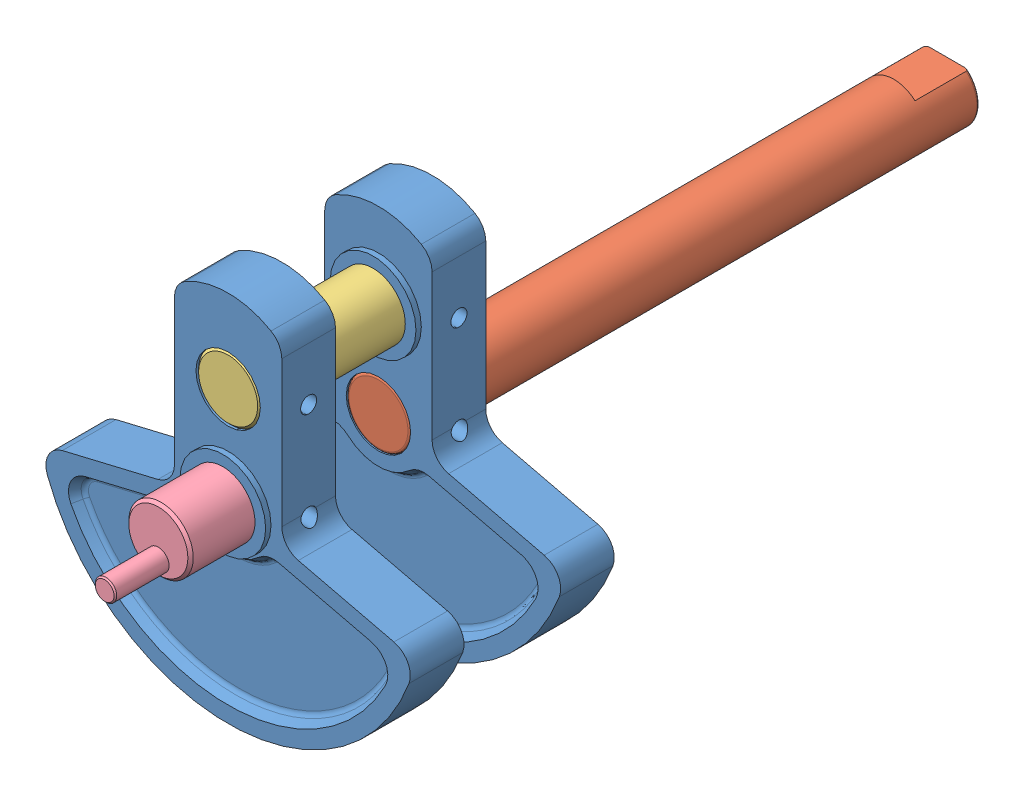
SolidWorks assembly Assembly Crankshaft, configuration Default. Lengths in mm.
Overall size (33.96 34.76 78.53).
5 component instances, 4 part files, 8 mates.
Components (placement in the parent):
- Crankshaft Counterweight-1: Crankshaft Counterweight [Default] at (4.4861 16.4045 32.7559) size (33.96 34.76 6)
- Crankshaft-3: Crankshaft [Default] at (4.4861 16.4045 35.2559) x (-1 0 0) z (0 0 -1) size (6 6 53.03)
- Crankshaft pin-1: Crankshaft pin [Default] at (4.4861 25.4045 30.2559) size (6 6 19)
- Crankshaft Counterweight-2: Crankshaft Counterweight [Default] at (4.4861 16.4045 46.7559) x (-1 0 0) z (0 0 -1) size (33.96 34.76 6)
- Crankshaft valve crank-1: Crankshaft valve crank [Default] at (4.4861 16.4045 44.2559) x (1 0 0) z (0 -1 0) size (6 16.5 6)
Mates (geometry in assembly coordinates):
- Coincident1: coincident aligned: line of Crankshaft Counterweight-1 through (9.4861 16.4045 32.7559) axis (-1 0 0); line of Crankshaft-3 through (7.4861 16.4045 32.7559) axis (-1 0 0)
- Concentric1: concentric aligned: cylinder of Crankshaft Counterweight-1 through (4.4861 16.4045 30.2559) axis (0 0 1) radius 3; cylinder of Crankshaft-3 through (4.4861 16.4045 -17.7441) axis (0 0 1) radius 3
- Coincident2: coincident anti-aligned: line of Crankshaft Counterweight-1 through (9.4861 25.4045 32.7559) axis (-1 0 0); line of Crankshaft pin-1 through (1.4861 25.4045 32.7559) axis (1 0 0)
- Concentric2: concentric anti-aligned: cylinder of Crankshaft Counterweight-1 through (4.4861 25.4045 29.7559) axis (0 0 1) radius 3; cylinder of Crankshaft pin-1 through (4.4861 25.4045 49.2559) axis (0 0 -1) radius 3
- Coincident3: coincident aligned: line of Crankshaft pin-1 through (1.4861 25.4045 46.7559) axis (1 0 0); line of Crankshaft Counterweight-2 through (7.4861 25.4045 46.7559) axis (1 0 0)
- Concentric3: concentric aligned: cylinder of Crankshaft pin-1 through (4.4861 25.4045 49.2559) axis (0 0 -1) radius 3; cylinder of Crankshaft Counterweight-2 through (4.4861 25.4045 49.7559) axis (0 0 -1) radius 3
- Concentric5: concentric: cylinder of assembly; line of assembly; cylinder of Crankshaft Counterweight-2 through (-12.4926 16.4045 46.7559) axis (1 0 0) radius 0.75; axis of Crankshaft valve crank-1 through (1.4861 16.4045 46.7559) axis (1 0 0)
- Concentric6: concentric aligned: cylinder of Crankshaft Counterweight-2 through (4.4861 16.4045 49.2559) axis (0 0 -1) radius 3; cylinder of Crankshaft valve crank-1 through (4.4861 16.4045 55.7559) axis (0 0 -1) radius 3
